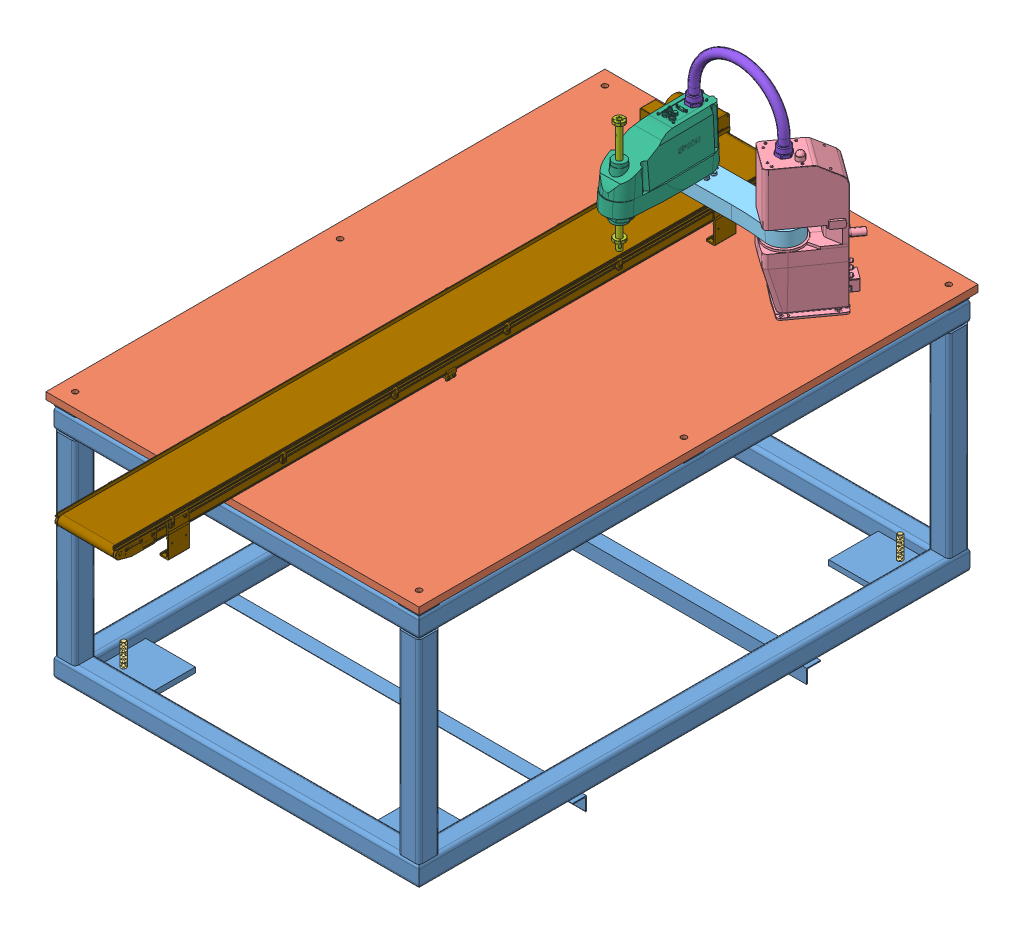
SolidWorks assembly TEST-AAA-AA, configuration Default. Lengths in mm.
Overall size (1355 1673.63 2529.38).
15 component instances, 10 part files, 4 mates.
Components (placement in the parent):
- TEST-BBB-AA-1: TEST-BBB-AA [Default] at (0 -535.5279 0) size (1355 977.03 2030)
  - TEST-BBB-AB-1: TEST-BBB-AB [Default<As Machined>] at (584.0128 1612.7119 1579.6915) size (1339.8 929.4 2000.2)
  - TEST-BBB-AC-1: TEST-BBB-AC [Default] at (584.0128 1638.1119 1579.6915) x (0 0 -1) z (-1 0 0) size (2030 25.4 1355)
  - 6111K257_SWIVEL LEVELING MOUNT-1: 6111K257_SWIVEL LEVELING MOUNT [Default] at (172.6128 661.0826 705.7915) size (76.2 193.68 76.2)
  - 6111K257_SWIVEL LEVELING MOUNT-2: 6111K257_SWIVEL LEVELING MOUNT [Default] at (1245.4128 661.0826 705.7915) size (76.2 193.68 76.2)
  - 6111K257_SWIVEL LEVELING MOUNT-3: 6111K257_SWIVEL LEVELING MOUNT [Default] at (1245.4128 661.0826 2453.5915) size (76.2 193.68 76.2)
  - 6111K257_SWIVEL LEVELING MOUNT-4: 6111K257_SWIVEL LEVELING MOUNT [Default] at (172.6128 661.0826 2453.5915) size (76.2 193.68 76.2)
- T6-602S-1: T6-602S [Default] at (1122.7914 1112.084 918.4769) x (0.808382 0 0.588658) z (-0.588658 0 0.808382) size (437.85 696.6 710.15)
  - _T6-602S_BASE_1_2-1: _T6-602S_BASE_1_2 [Default] x (0 0 1) z (-1 0 0) size (277.81 491 169.01)
  - _T6-602S_ARM1_1_2-1: _T6-602S_ARM1_1_2 [Default] at (0 200 62.5) x (-0.805129 0 0.5931) z (-0.5931 0 -0.805129) size (440.55 67 122.71)
  - _T6-602S_ARM2_1_2-1: _T6-602S_ARM2_1_2 [Default] at (-96.5718 265 475.1859) x (0.600346 0 0.79974) z (-0.79974 0 0.600346) size (392.25 248.41 135.51)
  - _T6-602S_SHAFT_1_2-1: _T6-602S_SHAFT_1_2 [Default] at (-96.5718 529.386 475.1859) x (0.999968 0 -0.007955) z (0.007955 0 0.999968) size (39.99 410 40)
  - _T6-602S_CABLE_1_2-1: _T6-602S_CABLE_1_2 [Default] at (-261.667 441.3 255.2573) x (0.5931 0 0.805129) z (-0.805129 0 0.5931) size (46.1 245.8 375.7)
  - _T6-602SWS-1: _T6-602SWS [Default] x (0 0 -1) z (1 0 0) size (1092.5 200 1200) (hidden)
- 5734K453_READY-TO-RUN MINI BELT CONVEYOR-1: 5734K453_READY-TO-RUN MINI BELT CONVEYOR [Default] at (673.0803 1212.2612 3016.4542) x (0.001606 0 -0.999999) z (0.999999 0 0.001606) size (2451.04 168.5 409.29)
Mates (geometry in assembly coordinates):
- Coincident1: coincident aligned: plane of TEST-BBB-AA-1 through (0 -535.5279 0) normal (1 0 0)
- Coincident2: coincident aligned: plane of TEST-BBB-AA-1 through (0 -535.5279 0) normal (0 0 1)
- Coincident3: coincident anti-aligned: plane of TEST-BBB-AA-1/TEST-BBB-AC-1 through (584.0128 1102.584 1579.6915) normal (0 1 0); plane of T6-602S-1/_T6-602S_BASE_1_2-1 through (997.089 1102.584 947.5525) normal (0 -1 0)
- Coincident4: coincident anti-aligned: plane of TEST-BBB-AA-1/TEST-BBB-AC-1 through (584.0128 1102.584 1579.6915) normal (0 1 0); plane of 5734K453_READY-TO-RUN MINI BELT CONVEYOR-1 through (595.164 1102.584 921.6392) normal (0 -1 0)
